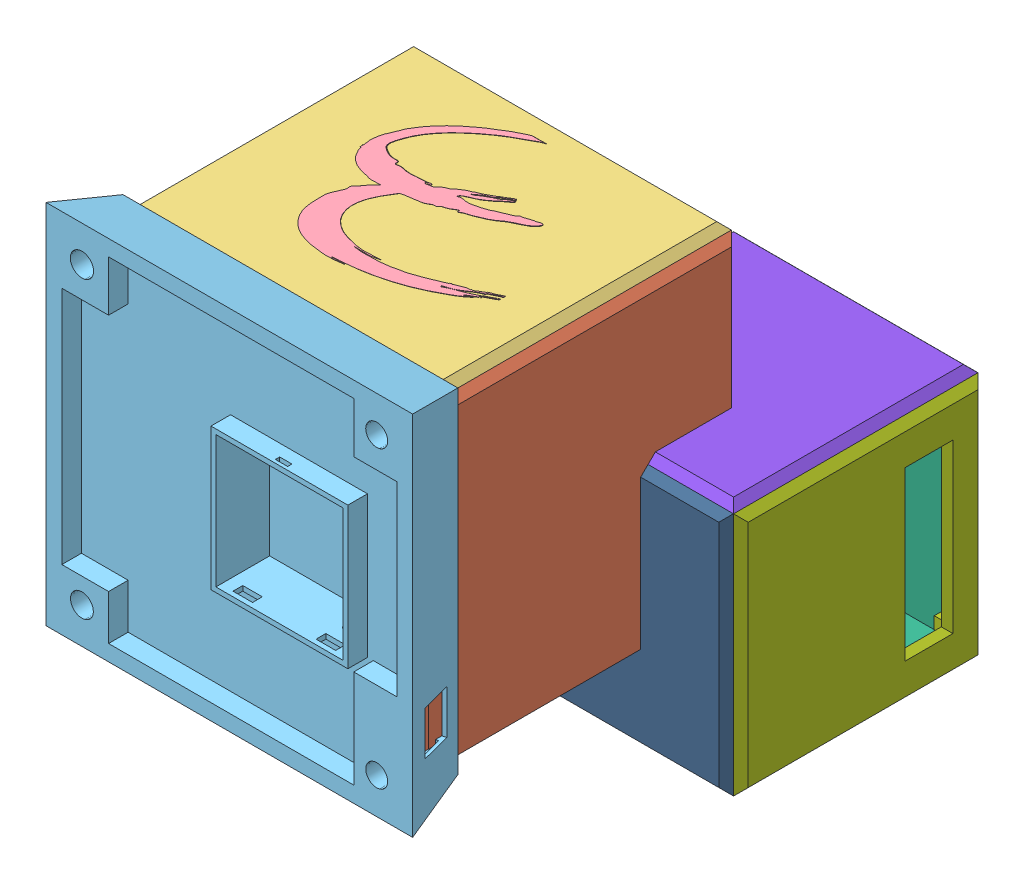
SolidWorks assembly cadeaux marraine, configuration Défaut. Lengths in mm.
Overall size (181.3 175.65 205.95).
15 component instances, 10 part files, 3 mates.
Components (placement in the parent):
- grand_cube-1: grand_cube [Défaut] at (-35.1677 41.1551 -196.1764) size (150 150 143)
  - cote_cubeb_top-1: cote_cubeb_top [Défaut] at (-79.2888 -63.7392 130.0001) size (130 130 17.9)
  - cote_cubeb_1-6: cote_cubeb_1 [Défaut] at (50.7112 -66.7392 133.0001) x (-1 0 0) z (0 1 0) size (130 130 13)
  - cote_cubeb_1-5: cote_cubeb_1 [Défaut] at (53.7112 66.2608 132.9001) x (0 -1 0) z (-1 0 0) size (130 130 13)
  - cote_cubeb_1-7: cote_cubeb_1 [Défaut] at (-82.2888 -63.7392 132.9001) x (0 1 0) z (1 0 0) size (130 130 13)
  - cote_cubeb_1_espilon-4: cote_cubeb_1_espilon [Défaut] at (-79.2888 69.2608 132.9001) x (1 0 0) z (0 -1 0) size (130 130 13)
  - epsilon_rouge-1: epsilon_rouge [Défaut] at (-11.9946 66.2608 185.5182) x (-0.999984 0 0.005736) z (0 1 0) size (85.8 85.09 3)
  - cote_cubeb_bot-2: cote_cubeb_bot [Défaut] at (-89.5888 75.9608 273.0001) x (1 0 0) z (0 0 -1) size (150 150 25)
- petit_cube-1: petit_cube [Défaut] at (24.7592 -152.0342 -72.678) x (1 0 0) z (0 1 0) size (106 105.95 105.9)
  - cote_cubeh_1-1: cote_cubeh_1 [Défaut] at (-71.2157 -46.5017 93.5) size (100 100 13)
  - Facade_lcd-1: Facade_lcd [Défaut] at (28.7843 -46.5017 196.45) x (0 0 -1) z (1 0 0) size (100 100 13)
  - cote_cubeh_1-2: cote_cubeh_1 [Défaut] at (28.7843 56.4483 96.5038) x (0 0 1) z (0 -1 0) size (100 100 13)
  - cote_cubeh_sym_mod-1: cote_cubeh_sym_mod [Défaut] at (-71.2157 -46.5017 193.4) size (100 100 13)
  - cote_cubeh_back-1: cote_cubeh_back [Défaut] at (-74.2194 53.4983 196.45) x (0 -1 0) z (1 0 0) size (100 100 13)
  - cote_cubeh_1_bot-1: cote_cubeh_1_bot [Défaut] at (28.7306 -49.5017 196.45) x (0 0 -1) z (0 1 0) size (100 100 13)
Mates (geometry in assembly coordinates):
- Coïncidente2: coincident anti-aligned: plane of grand_cube-1/cote_cubeb_1-5 through (18.5435 107.4158 -63.2763) normal (1 0 0); plane of petit_cube-1/cote_cubeh_sym_mod-1 through (18.5435 54.3658 -66.1763) normal (-1 0 0)
- Coïncidente3: coincident anti-aligned: plane of grand_cube-1/cote_cubeb_top-1 through (-114.4565 -22.5842 -66.1763) normal (0 0 -1); plane of petit_cube-1/cote_cubeh_sym_mod-1 through (-46.4065 34.3658 -66.1763) normal (0 0 1)
- Coïncidente4: coincident anti-aligned: plane of grand_cube-1/cote_cubeb_1-6 through (15.5435 -25.5842 -63.1763) normal (0 -1 0); plane of petit_cube-1/cote_cubeh_1_bot-1 through (18.4898 -25.5842 -16.1763) normal (0 1 0)
